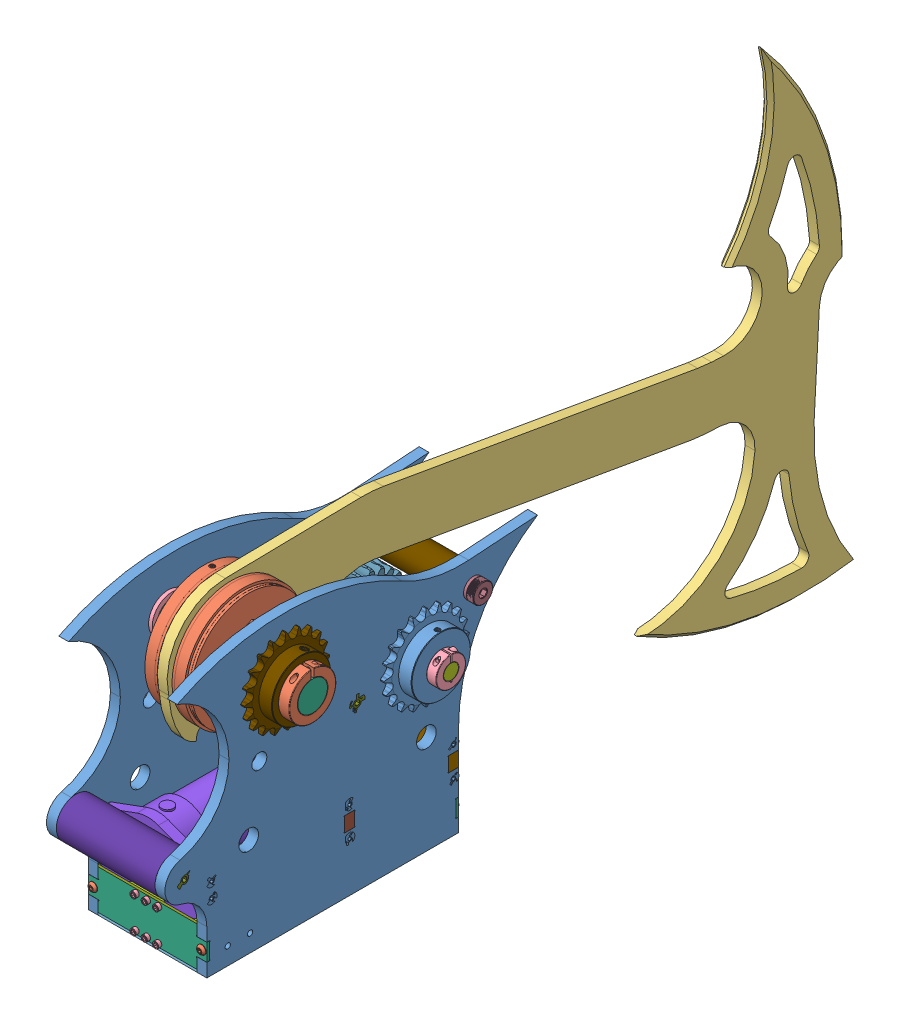
SolidWorks assembly BombshellAxeAsm, configuration Extend. Lengths in mm.
99 component instances, 41 part files, 194 mates.
Components (placement in the parent):
- AxeWeaponRail-1: AxeWeaponRail [Default] at (439.7489 345.0261 495.1514) size (12.7 356.85 479.43)
- AxeWeaponRail-2: AxeWeaponRail [Default] at (300.0489 345.0261 495.1514) size (12.7 356.85 479.43)
- AxeArmAsm-1: AxeArmAsm [Default] at (391.7765 573.6147 629.7988) x (0 -0.054175 -0.998531) z (1 0 0) size (901.7 632 77.46)
  - 6524K135 440ftlb Torque Clutch 1500bore-1: 6524K135 440ftlb Torque Clutch 1500bore [6524K135] at (-33.243 17.2859 43.2099) size (152.4 152.56 77.46)
  - AxeBarV2-1: AxeBarV2 [Default] at (-33.243 17.2859 -17.1151) x (0 0 1) z (-1 0 0) size (12.7 632 901.7)
- 6338K442 1500ID Bushing-1: 6338K442 1500ID Bushing [Default] at (434.9864 592.6761 662.0565) size (38.1 50.8 50.8)
- 6338K442 1500ID Bushing-2: 6338K442 1500ID Bushing [Default] at (317.5114 592.6761 662.0565) x (-1 0 0) z (0 -0.924225 -0.381849) size (38.1 50.8 50.8)
- AxePodBottom-1: AxePodBottom [Default] at (439.7489 300.5761 752.19) x (0 0 -1) z (1 0 0) size (323.85 3.17 127)
- AxePodFrontRearPlate-1: AxePodFrontRearPlate [Default] at (312.7489 303.7511 428.34) size (152.4 50.8 3.18)
- AxePodFrontRearPlate-2: AxePodFrontRearPlate [Default] at (312.7489 303.7511 749.015) size (152.4 50.8 3.18)
- AxePodTop-1: AxePodTop [Default] at (439.7489 354.5511 752.19) x (0 0 -1) z (1 0 0) size (323.85 3.17 127)
- s28400mag-1: s28400mag [Default] at (376.2489 402.1761 739.49) x (0 1 0) z (0 0 -1) size (82.57 82.57 225.04)
- NanoTech 4S 5000mah 130C pack-1: NanoTech 4S 5000mah 130C pack [Default] at (319.0989 340.7511 599.4047) x (0 0 -1) z (0 -1 0) size (178.4 49 37)
- NanoTech 4S 5000mah 130C pack-2: NanoTech 4S 5000mah 130C pack [Default] at (368.0989 340.7511 599.4047) x (0 0 -1) z (0 -1 0) size (178.4 49 37)
- MS2-1: MS2 [Default] at (312.7489 313.1491 682.34) x (0 0 1) z (-1 0 0) size (57.15 41.4 43.43)
- ragebridge2 lpm assembly-1: ragebridge2 lpm assembly [Default] at (323.5439 354.5511 625.19) x (1 0 0) z (0 -1 0) size (105.41 63.5 21.77)
  - heatsink 0002-1: heatsink 0002 [Default] at origin size (93.98 63.5 3.17)
  - ragebridge2 lpm-1: ragebridge2 lpm [Default] at (52.705 25.4 3.175) x (1 0 0) z (0 -1 0) size (105.41 18.6 50.8)
- ragebridge2 lpm assembly-2: ragebridge2 lpm assembly [Default] at (323.5439 303.7511 675.99) x (1 0 0) z (0 1 0) size (105.41 63.5 21.77)
  - heatsink 0002-1: heatsink 0002 [Default] at origin size (93.98 63.5 3.17)
  - ragebridge2 lpm-1: ragebridge2 lpm [Default] at (52.705 25.4 3.175) x (1 0 0) z (0 -1 0) size (105.41 18.6 50.8)
- OrangeRX R410-1: OrangeRX R410 [Default] at (373.9489 346.5511 729.1047) size (15 8 37)
- 57545K213 24T 6P Worm for 0750 Shaft-1: 57545K213 24T 6P Worm for 0750 Shaft [57545K213] at (376.2489 529.1761 482.4514) x (0 0 -1) z (-1 0 0) size (116.49 116.49 50.43)
- Gear48T16P_6325K21 MOD FOR LIFTER-1: Gear48T16P_6325K21 MOD FOR LIFTER [Default] at (376.2489 452.9761 559.023) x (0 0 -1) z (1 0 0) size (25.4 79.5 79.5)
- 57545K227 6P Motor Side Worm for 0875in Shaft-1: 57545K227 6P Motor Side Worm for 0875in Shaft [57545K227] at (376.2489 452.9761 482.4514) size (59.94 60.18 68.33)
- Gear16T16P_6325K13-1: Gear16T16P_6325K13 [Default] at (376.2489 402.1761 559.023) x (0 0 -1) z (1 0 0) size (23.81 28.7 28.7)
- 6280K978 Lifter Large Sprocket-1: 6280K978 Lifter Large Sprocket [6280K978] at (463.155 592.6761 662.0565) x (0 -0.288312 -0.957536) z (1 0 0) size (109.73 109.73 25.4)
- 6280K970 Sprocket 20t Num50 0750Bore-1: 6280K970 Sprocket 20t Num50 0750Bore [6280K97] at (463.155 529.1761 482.4514) x (0 0 -1) z (1 0 0) size (109.73 109.73 25.4)
- 6157K230 1500in Shaft Collar Alu-2: 6157K230 1500in Shaft Collar Alu [6157K23] at (351.6427 592.6761 662.0565) x (0 0 1) z (-1 0 0) size (60.32 60.31 14.37)
- 6157K230 1500in Shaft Collar Alu-3: 6157K230 1500in Shaft Collar Alu [6157K23] at (491.3427 592.6761 662.0565) x (0 0 1) z (-1 0 0) size (60.32 60.31 14.37)
- 6338K431 0750 Bushing-1: 6338K431 0750 Bushing [Default] at (434.9864 529.1761 482.4514) x (-1 0 0) z (0 -0.924225 -0.381849) size (15.88 31.75 31.75)
- 6338K431 0750 Bushing-2: 6338K431 0750 Bushing [Default] at (317.5114 529.1761 482.4514) size (15.88 31.75 31.75)
- 6157K160 0750 Shaft Collar-1: 6157K160 0750 Shaft Collar [6157K16] at (490.5489 529.1761 482.4514) x (0 0 1) z (-1 0 0) size (38.1 38.11 12.77)
- 6157K160 0750 Shaft Collar-2: 6157K160 0750 Shaft Collar [6157K16] at (417.5239 529.1761 482.4514) x (0 0 1) z (-1 0 0) size (38.1 38.11 12.77)
- 6157K160 0750 Shaft Collar-3: 6157K160 0750 Shaft Collar [6157K16] at (357.1989 529.1761 482.4514) x (0 0 1) z (-1 0 0) size (38.1 38.11 12.77)
- 6157K160 0750 Shaft Collar-4: 6157K160 0750 Shaft Collar [6157K16] at (290.5239 529.1761 482.4514) x (0 -0.246824 0.96906) z (-1 0 0) size (38.1 38.11 12.77)
- 6157K230 1500in Shaft Collar Alu-4: 6157K230 1500in Shaft Collar Alu [6157K23] at (289.7302 592.6761 662.0565) x (0 0 -1) z (1 0 0) size (60.32 60.31 14.37)
- 6157K170 0875 Shaft Collar-2: 6157K170 0875 Shaft Collar [6157K17] at (376.2489 452.9761 520.5514) size (41.27 41.28 12.77)
- AxeMainShaft-1: AxeMainShaft [Default] at (390.5364 592.6761 662.0565) x (1 0 0) z (0 0.225652 -0.974208) size (215.9 38.1 38.1)
- AxeChainShaft-1: AxeChainShaft [Default] at (390.5364 529.1761 482.4514) x (1 0 0) z (0 -0.621603 -0.783332) size (212.72 19.05 19.05)
- LongMagRearMount-1: LongMagRearMount [Default] at (376.2489 357.7261 739.49) size (127 84.14 12.7)
- WormShaftMount1-1: WormShaftMount1 [Default] at (376.2489 357.7261 428.34) size (152.4 127 12.7)
- 2868T195 0875 Sleeve Bushing no flange 1125OD-1: 2868T195 0875 Sleeve Bushing no flange 1125OD [2868T195] at (376.2489 452.9761 441.04) size (28.57 28.57 25.4)
- WormShaftMount2-1: WormShaftMount2 [Default] at (376.2489 357.7261 562.198) size (152.4 120.65 12.7)
- 2868T195 0875 Sleeve Bushing no flange 1125OD-2: 2868T195 0875 Sleeve Bushing no flange 1125OD [2868T195] at (376.2489 452.9761 562.198) size (28.57 28.57 25.4)
- LowerWormShaft-1: LowerWormShaft [Default] at (376.2489 452.9761 495.015) x (0 0 -1) z (1 0 0) size (158.75 22.23 22.23)
- 6157K170 0875 Shaft Collar-4: 6157K170 0875 Shaft Collar [6157K17] at (376.2489 452.9761 421.99) x (0.927801 -0.373074 0) z (0 0 1) size (41.27 41.28 12.77)
- 91259A860 0750 Shoulder Bolt for Axe Stop-1: 91259A860 0750 Shoulder Bolt for Axe Stop [91259A860] at (452.4489 564.1011 409.29) x (0 -0.381849 0.924225) z (0 0.924225 0.381849) size (25.4 188.12 25.4)
- 97135A270 0625-11 Locknut-1: 97135A270 0625-11 Locknut [97135A270] at (300.0489 564.1011 409.29) x (0 1 0) z (0 0 1) size (23.81 19.79 27.5)
- module standoffs-1: module standoffs [Default] at (312.7489 424.4011 780.765) size (127 22.23 22.23)
- module standoffs-2: module standoffs [Default] at (312.7489 510.1261 558.515) size (127 22.23 22.23)
- 91253A624-1: 91253A624 [91253A624] at (452.4489 510.1261 558.515) x (0 0 -1) z (1 0 0) size (19.84 19.84 26.24)
- 91253A624-2: 91253A624 [91253A624] at (452.4489 424.4011 780.765) x (0 0 -1) z (1 0 0) size (19.84 19.84 26.24)
- 91253A624-3: 91253A624 [91253A624] at (300.0489 510.1261 558.515) x (0 0 1) z (-1 0 0) size (19.84 19.84 26.24)
- 91253A624-4: 91253A624 [91253A624] at (300.0489 424.4011 780.765) x (0 0 1) z (-1 0 0) size (19.84 19.84 26.24)
- 87235k58 polyurethane tube trimmed to 5in-1: 87235k58 polyurethane tube trimmed to 5in [Default] at (376.2489 424.4011 780.765) size (127 50.8 50.8)
- 9697k158 polyurethane tube trimmed to 5in-1: 9697k158 polyurethane tube trimmed to 5in [Default] at (376.2489 564.1011 409.29) size (127 38.1 38.1)
- 91253A542 0250-20 x 1 FHCS-1: 91253A542 0250-20 x 1 FHCS [91253A542] at (300.0489 405.2646 745.84) x (0 0 1) z (-1 0 0) size (13.49 13.49 26.08)
- 91253A542 0250-20 x 1 FHCS-2: 91253A542 0250-20 x 1 FHCS [91253A542] at (300.0489 386.2146 745.84) x (0 0 1) z (-1 0 0) size (13.49 13.49 26.08)
- 91253A542 0250-20 x 1 FHCS-3: 91253A542 0250-20 x 1 FHCS [91253A542] at (300.0489 402.1761 568.548) x (0 0 1) z (-1 0 0) size (13.49 13.49 26.08)
- 91253A542 0250-20 x 1 FHCS-4: 91253A542 0250-20 x 1 FHCS [91253A542] at (300.0489 364.0761 568.548) x (0 0 1) z (-1 0 0) size (13.49 13.49 26.08)
- 91253A542 0250-20 x 1 FHCS-5: 91253A542 0250-20 x 1 FHCS [91253A542] at (300.0489 402.1761 434.69) x (0 0 1) z (-1 0 0) size (13.49 13.49 26.08)
- 91253A542 0250-20 x 1 FHCS-6: 91253A542 0250-20 x 1 FHCS [91253A542] at (300.0489 364.0761 434.69) x (0 0 1) z (-1 0 0) size (13.49 13.49 26.08)
- 91255A539 0250-20 x 0625 BHCS-1: 91255A539 0250-20 x 0625 BHCS [91255A539] at (306.3989 329.1511 755.5428) size (11.1 11.1 19.9)
- 91255A539 0250-20 x 0625 BHCS-2: 91255A539 0250-20 x 0625 BHCS [91255A539] at (306.3989 329.1511 424.9872) x (-0.923728 -0.383049 0) z (0 0 -1) size (11.1 11.1 19.9)
- 91253A542 0250-20 x 1 FHCS-7: 91253A542 0250-20 x 1 FHCS [91253A542] at (452.4489 405.2646 745.84) x (0 0 1) z (1 0 0) size (13.49 13.49 26.08)
- 91253A542 0250-20 x 1 FHCS-8: 91253A542 0250-20 x 1 FHCS [91253A542] at (452.4489 386.2146 745.84) x (0 0 1) z (1 0 0) size (13.49 13.49 26.08)
- 91253A542 0250-20 x 1 FHCS-9: 91253A542 0250-20 x 1 FHCS [91253A542] at (452.4489 402.1761 568.548) x (0 0 1) z (1 0 0) size (13.49 13.49 26.08)
- 91253A542 0250-20 x 1 FHCS-10: 91253A542 0250-20 x 1 FHCS [91253A542] at (452.4489 364.0761 568.548) x (0 0 1) z (1 0 0) size (13.49 13.49 26.08)
- 91253A542 0250-20 x 1 FHCS-11: 91253A542 0250-20 x 1 FHCS [91253A542] at (452.4489 402.1761 434.69) x (0 0 1) z (1 0 0) size (13.49 13.49 26.08)
- 91253A542 0250-20 x 1 FHCS-12: 91253A542 0250-20 x 1 FHCS [91253A542] at (452.4489 364.0761 434.69) x (0 0 1) z (1 0 0) size (13.49 13.49 26.08)
- 91255A539 0250-20 x 0625 BHCS-3: 91255A539 0250-20 x 0625 BHCS [91255A539] at (446.0989 329.1511 755.5428) x (-1 0 0) z (0 0 1) size (11.1 11.1 19.9)
- 91255A539 0250-20 x 0625 BHCS-4: 91255A539 0250-20 x 0625 BHCS [91255A539] at (446.0989 329.1511 424.9872) x (0.923728 -0.383049 0) z (0 0 -1) size (11.1 11.1 19.9)
- 3x2 Medium Nutstrip-1: 3x2 Medium Nutstrip [Default] at (357.1989 308.5136 436.2775) x (1 0 0) z (0 1 0) size (38.1 9.53 9.53)
- 3x2 Medium Nutstrip-2: 3x2 Medium Nutstrip [Default] at (357.1989 349.7886 436.2775) x (1 0 0) z (0 1 0) size (38.1 9.53 9.53)
- 3x2 Medium Nutstrip-3: 3x2 Medium Nutstrip [Default] at (357.1989 349.7886 744.2525) x (1 0 0) z (0 1 0) size (38.1 9.53 9.53)
- 3x2 Medium Nutstrip-4: 3x2 Medium Nutstrip [Default] at (357.1989 308.5136 744.2525) x (1 0 0) z (0 1 0) size (38.1 9.53 9.53)
- 91251A242 10-24 SHCS 0500L-1: 91251A242 10-24 SHCS 0500L [91251A242] at (390.7489 308.5136 739.49) x (-0.923728 -0.383049 0) z (0 0 -1) size (7.92 7.92 18.68)
- 91253A242 10-24x0500 FHCS-1: 91253A242 10-24x0500 FHCS [91253A242] at (368.9989 300.5761 744.2525) x (1 0 0) z (0 -1 0) size (10.44 10.44 25.75)
- 91251A242 10-24 SHCS 0500L-2: 91251A242 10-24 SHCS 0500L [91251A242] at (376.2489 308.5136 739.49) x (-0.923728 -0.383049 0) z (0 0 -1) size (7.92 7.92 18.68)
- 91251A242 10-24 SHCS 0500L-3: 91251A242 10-24 SHCS 0500L [91251A242] at (361.7489 308.5136 739.49) x (-0.923728 -0.383049 0) z (0 0 -1) size (7.92 7.92 18.68)
- 91251A242 10-24 SHCS 0500L-4: 91251A242 10-24 SHCS 0500L [91251A242] at (390.7489 349.7886 739.49) x (-0.923728 -0.383049 0) z (0 0 -1) size (7.92 7.92 18.68)
- 91251A242 10-24 SHCS 0500L-5: 91251A242 10-24 SHCS 0500L [91251A242] at (376.2489 349.7886 739.49) x (-0.923728 -0.383049 0) z (0 0 -1) size (7.92 7.92 18.68)
- 91251A242 10-24 SHCS 0500L-6: 91251A242 10-24 SHCS 0500L [91251A242] at (361.7489 349.7886 739.49) x (-0.923728 -0.383049 0) z (0 0 -1) size (7.92 7.92 18.68)
- 91251A242 10-24 SHCS 0500L-7: 91251A242 10-24 SHCS 0500L [91251A242] at (368.9989 345.0261 744.2525) x (1 0 0) z (0 -1 0) size (7.92 7.92 18.68)
- 91251A242 10-24 SHCS 0500L-8: 91251A242 10-24 SHCS 0500L [91251A242] at (383.4989 345.0261 744.2525) x (1 0 0) z (0 -1 0) size (7.92 7.92 18.68)
- 91251A242 10-24 SHCS 0500L-9: 91251A242 10-24 SHCS 0500L [91251A242] at (390.7489 308.5136 441.04) size (7.92 7.92 18.68)
- 91251A242 10-24 SHCS 0500L-10: 91251A242 10-24 SHCS 0500L [91251A242] at (376.2489 308.5136 441.04) size (7.92 7.92 18.68)
- 91251A242 10-24 SHCS 0500L-11: 91251A242 10-24 SHCS 0500L [91251A242] at (361.7489 308.5136 441.04) size (7.92 7.92 18.68)
- 91251A242 10-24 SHCS 0500L-12: 91251A242 10-24 SHCS 0500L [91251A242] at (390.7489 349.7886 441.04) size (7.92 7.92 18.68)
- 91251A242 10-24 SHCS 0500L-13: 91251A242 10-24 SHCS 0500L [91251A242] at (376.2489 349.7886 441.04) size (7.92 7.92 18.68)
- 91251A242 10-24 SHCS 0500L-14: 91251A242 10-24 SHCS 0500L [91251A242] at (361.7489 349.7886 441.04) size (7.92 7.92 18.68)
- 91251A242 10-24 SHCS 0500L-15: 91251A242 10-24 SHCS 0500L [91251A242] at (368.9989 345.0261 436.2775) x (1 0 0) z (0 -1 0) size (7.92 7.92 18.68)
- 91251A242 10-24 SHCS 0500L-16: 91251A242 10-24 SHCS 0500L [91251A242] at (383.4989 345.0261 436.2775) x (1 0 0) z (0 -1 0) size (7.92 7.92 18.68)
- 91253A242 10-24x0500 FHCS-2: 91253A242 10-24x0500 FHCS [91253A242] at (383.4989 300.5761 744.2525) x (1 0 0) z (0 -1 0) size (10.44 10.44 25.75)
- 91253A242 10-24x0500 FHCS-3: 91253A242 10-24x0500 FHCS [91253A242] at (368.9989 300.5761 436.2775) x (1 0 0) z (0 -1 0) size (10.44 10.44 25.75)
- 91253A242 10-24x0500 FHCS-4: 91253A242 10-24x0500 FHCS [91253A242] at (383.4989 300.5761 436.2775) x (1 0 0) z (0 -1 0) size (10.44 10.44 25.75)
- 91253A542 0250-20 x 1 FHCS-13: 91253A542 0250-20 x 1 FHCS [91253A542] at (300.0489 322.8011 696.564) x (0 0 1) z (-1 0 0) size (13.49 13.49 26.08)
- 91253A542 0250-20 x 1 FHCS-14: 91253A542 0250-20 x 1 FHCS [91253A542] at (300.0489 322.8011 725.266) x (0 0 1) z (-1 0 0) size (13.49 13.49 26.08)
Mates (geometry in assembly coordinates):
- Distance7: distance = 4.7625 mm anti-aligned: plane of AxeWeaponRail-1 through (439.7489 345.0261 495.1514) normal (-1 0 0); plane of AxeArmAsm-1/6524K135 440ftlb Torque Clutch 1500bore-1 through (434.9864 611.6982 661.0245) normal (1 0 0)
- Coincident64: coincident anti-aligned: plane of AxeWeaponRail-1 through (439.7489 345.0261 495.1514) normal (-1 0 0); plane of 6338K442 1500ID Bushing-1 through (439.7489 592.6761 662.0565) normal (1 0 0)
- Coincident65: coincident anti-aligned: plane of AxeWeaponRail-2 through (312.7489 345.0261 495.1514) normal (1 0 0); plane of 6338K442 1500ID Bushing-2 through (312.7489 592.6761 662.0565) normal (-1 0 0)
- Concentric60: concentric aligned: cylinder of AxeWeaponRail-1 through (439.7489 427.5761 469.7514) axis (1 0 0) radius 12.7; cylinder of AxeWeaponRail-2 through (300.0489 427.5761 469.7514) axis (1 0 0) radius 12.7
- Concentric61: concentric aligned: cylinder of AxeWeaponRail-1 through (439.7489 427.5761 698.3514) axis (1 0 0) radius 12.7; cylinder of AxeWeaponRail-2 through (300.0489 427.5761 698.3514) axis (1 0 0) radius 12.7
- Distance8: distance = 152.4 mm anti-aligned: plane of AxeWeaponRail-2 through (300.0489 345.0261 495.1514) normal (-1 0 0); plane of AxeWeaponRail-1 through (452.4489 345.0261 495.1514) normal (1 0 0)
- Coincident66: coincident anti-aligned: plane of AxeWeaponRail-2 through (312.7489 345.0261 495.1514) normal (1 0 0); plane of AxePodBottom-1 through (312.7489 303.7511 752.19) normal (-1 0 0)
- Coincident67: coincident aligned: plane of AxeWeaponRail-1 through (439.7489 418.1311 428.34) normal (0 0 -1); plane of AxePodBottom-1 through (439.7489 303.7511 428.34) normal (0 0 -1)
- Coincident68: coincident aligned: plane of AxeWeaponRail-1 through (452.4489 300.5761 495.1514) normal (0 -1 0); plane of AxePodBottom-1 through (439.7489 300.5761 752.19) normal (0 -1 0)
- Coincident75: coincident anti-aligned: plane of AxeWeaponRail-1 through (439.7489 345.0261 495.1514) normal (-1 0 0); plane of AxePodTop-1 through (439.7489 357.7261 752.19) normal (1 0 0)
- Coincident77: coincident aligned: plane of AxeWeaponRail-1 through (439.7489 418.1311 428.34) normal (0 0 -1); plane of AxePodTop-1 through (439.7489 357.7261 428.34) normal (0 0 -1)
- Parallel1: parallel aligned: plane of AxeWeaponRail-1 through (439.7489 300.5761 752.19) normal (0 0 1); plane of s28400mag-1 through (376.2489 402.1761 739.49) normal (0 0 1)
- Distance9: distance = 12.7 mm aligned: plane of s28400mag-1 through (376.2489 402.1761 739.49) normal (0 0 1); plane of AxeWeaponRail-1 through (439.7489 300.5761 752.19) normal (0 0 1)
- Distance11: distance = 57.15 mm anti-aligned: cylinder of s28400mag-1 through (376.2489 402.1761 755.492) axis (0 0 -1) radius 6.35; plane of AxeWeaponRail-1 through (439.7489 345.0261 495.1514) normal (-1 0 0)
- Coincident78: coincident aligned: plane of NanoTech 4S 5000mah 130C pack-1 through (368.0989 340.7511 599.4047) normal (0 1 0); plane of NanoTech 4S 5000mah 130C pack-2 through (417.0989 340.7511 599.4047) normal (0 1 0)
- Coincident79: coincident aligned: plane of NanoTech 4S 5000mah 130C pack-1 through (368.0989 340.7511 599.4047) normal (0 0 1); plane of NanoTech 4S 5000mah 130C pack-2 through (417.0989 340.7511 599.4047) normal (0 0 1)
- Coincident80: coincident anti-aligned: plane of NanoTech 4S 5000mah 130C pack-1 through (368.0989 340.7511 599.4047) normal (1 0 0); plane of NanoTech 4S 5000mah 130C pack-2 through (368.0989 340.7511 599.4047) normal (-1 0 0)
- Coincident81: coincident anti-aligned: plane of AxePodBottom-1 through (439.7489 303.7511 752.19) normal (0 1 0); plane of NanoTech 4S 5000mah 130C pack-1 through (368.0989 303.7511 599.4047) normal (0 -1 0)
- Parallel3: parallel anti-aligned: plane of AxeWeaponRail-2 through (312.7489 345.0261 495.1514) normal (1 0 0); plane of NanoTech 4S 5000mah 130C pack-1 through (319.0989 340.7511 599.4047) normal (-1 0 0)
- Distance12: distance = 6.35 mm anti-aligned: plane of AxeWeaponRail-2 through (312.7489 345.0261 495.1514) normal (1 0 0); plane of NanoTech 4S 5000mah 130C pack-1 through (319.0989 340.7511 599.4047) normal (-1 0 0)
- Coincident83: coincident anti-aligned: plane of AxeWeaponRail-2 through (312.7489 345.0261 495.1514) normal (1 0 0); plane of MS2-1 through (312.7489 354.5511 682.34) normal (-1 0 0)
- Coincident85: coincident anti-aligned: plane of AxePodTop-1 through (439.7489 354.5511 752.19) normal (0 -1 0); plane of ragebridge2 lpm assembly-1/heatsink 0002-1 through (421.9689 354.5511 618.205) normal (0 1 0)
- Distance15: distance = 10.795 mm anti-aligned: plane of AxeWeaponRail-1 through (439.7489 345.0261 495.1514) normal (-1 0 0); plane of ragebridge2 lpm assembly-1/ragebridge2 lpm-1 through (428.9539 351.3761 625.19) normal (1 0 0)
- Concentric62: concentric aligned: cylinder of ragebridge2 lpm assembly-1/heatsink 0002-1 through (414.3489 354.5511 679.165) axis (0 -1 0) radius 1.4605; cylinder of ragebridge2 lpm assembly-2/heatsink 0002-1 through (414.3489 306.9261 679.165) axis (0 -1 0) radius 1.4605
- Concentric63: concentric aligned: cylinder of ragebridge2 lpm assembly-1/heatsink 0002-1 through (338.1489 351.3761 622.015) axis (0 1 0) radius 1.4605; cylinder of ragebridge2 lpm assembly-2/heatsink 0002-1 through (338.1489 303.7511 622.015) axis (0 1 0) radius 1.4605
- Distance17: distance = 50.8 mm aligned: plane of ragebridge2 lpm assembly-2/heatsink 0002-1 through (421.9689 303.7511 682.975) normal (0 -1 0); plane of AxePodTop-1 through (439.7489 354.5511 752.19) normal (0 -1 0)
- Coincident89: coincident anti-aligned: plane of AxePodTop-1 through (439.7489 354.5511 752.19) normal (0 -1 0); plane of OrangeRX R410-1 through (373.9489 354.5511 729.1047) normal (0 1 0)
- Distance19: distance = 50.8 mm anti-aligned: plane of OrangeRX R410-1 through (388.9489 354.5511 729.1047) normal (1 0 0); plane of AxeWeaponRail-1 through (439.7489 345.0261 495.1514) normal (-1 0 0)
- Coincident92: coincident anti-aligned: plane of AxePodTop-1 through (439.7489 354.5511 752.19) normal (0 -1 0); plane of MS2-1 through (341.4509 354.5511 682.34) normal (0 1 0)
- Coincident93: coincident aligned: plane of Gear48T16P_6325K21 MOD FOR LIFTER-1 through (376.2489 452.9761 559.023) normal (0 0 1); plane of Gear16T16P_6325K13-1 through (376.2489 402.1761 559.023) normal (0 0 1)
- Distance20: distance = 33.3375 mm: cylinder of Gear48T16P_6325K21 MOD FOR LIFTER-1 through (376.2489 452.9761 533.623) axis (0 0 1) radius 11.1125; cylinder of Gear16T16P_6325K13-1 through (376.2489 402.1761 535.2105) axis (0 0 1) radius 6.35
- Parallel4: parallel anti-aligned: plane of s28400mag-1 through (376.2489 402.1761 566.008) normal (0 0 -1); plane of Gear16T16P_6325K13-1 through (376.2489 402.1761 559.023) normal (0 0 1)
- Concentric65: concentric aligned: cylinder of s28400mag-1 through (376.2489 402.1761 530.448) axis (0 0 1) radius 6.35; cylinder of Gear16T16P_6325K13-1 through (376.2489 402.1761 535.2105) axis (0 0 1) radius 6.35
- Distance21: distance = 9.525 mm anti-aligned: plane of Gear16T16P_6325K13-1 through (376.2489 402.1761 559.023) normal (0 0 1); plane of s28400mag-1 through (376.2489 402.1761 568.548) normal (0 0 -1)
- Concentric66: concentric aligned: cylinder of Gear48T16P_6325K21 MOD FOR LIFTER-1 through (376.2489 452.9761 533.623) axis (0 0 1) radius 11.1125; cylinder of 57545K227 6P Motor Side Worm for 0875in Shaft-1 through (376.2489 452.9761 482.4514) axis (0 0 1) radius 11.1125
- Parallel5: parallel aligned: plane of AxeWeaponRail-1 through (439.7489 345.0261 495.1514) normal (-1 0 0); plane of 57545K227 6P Motor Side Worm for 0875in Shaft-1 through (378.6302 463.1742 448.1299) normal (-1 0 0)
- Coincident95: coincident aligned: plane of Gear48T16P_6325K21 MOD FOR LIFTER-1 through (378.6302 452.9761 533.623) normal (-1 0 0); plane of 57545K227 6P Motor Side Worm for 0875in Shaft-1 through (378.6302 463.1742 448.1299) normal (-1 0 0)
- Coincident96: coincident anti-aligned: plane of 57545K213 24T 6P Worm for 0750 Shaft-1 through (376.2489 529.1761 482.4514) normal (-1 0 0); plane of 57545K227 6P Motor Side Worm for 0875in Shaft-1 through (376.2489 452.9761 482.4514) normal (1 0 0)
- Coincident97: coincident anti-aligned: plane of 57545K213 24T 6P Worm for 0750 Shaft-1; plane of 57545K227 6P Motor Side Worm for 0875in Shaft-1 through (376.2489 452.9761 482.4514) normal (0 0 1)
- Distance22: distance = 76.2 mm anti-aligned: plane of 57545K227 6P Motor Side Worm for 0875in Shaft-1 through (376.2489 452.9761 482.4514) normal (0 1 0); plane of 57545K213 24T 6P Worm for 0750 Shaft-1
- Distance23: distance = 52.3875 mm anti-aligned: cylinder of 57545K227 6P Motor Side Worm for 0875in Shaft-1 through (376.2489 452.9761 482.4514) axis (0 0 1) radius 11.1125; plane of AxeWeaponRail-2 through (312.7489 345.0261 495.1514) normal (1 0 0)
- Concentric67: concentric aligned: cylinder of 6338K442 1500ID Bushing-1 through (473.0864 592.6761 662.0565) axis (-1 0 0) radius 19.05; cylinder of 6280K978 Lifter Large Sprocket-1 through (484.1989 592.6761 662.0565) axis (-1 0 0) radius 19.05
- Distance24: distance = 6.35 mm anti-aligned: plane of AxeWeaponRail-1 through (452.4489 345.0261 495.1514) normal (1 0 0); plane of 6280K978 Lifter Large Sprocket-1 through (458.7989 547.729 675.59) normal (-1 0 0)
- Coincident100: coincident aligned: plane of 6280K978 Lifter Large Sprocket-1 through (458.7989 547.729 675.59) normal (-1 0 0); plane of 6280K970 Sprocket 20t Num50 0750Bore-1 through (458.7989 482.2357 482.4514) normal (-1 0 0)
- Concentric68: concentric anti-aligned: cylinder of AxeWeaponRail-1 through (439.7489 529.1761 482.4514) axis (1 0 0) radius 12.7; cylinder of 6280K970 Sprocket 20t Num50 0750Bore-1 through (484.1989 529.1761 482.4514) axis (-1 0 0) radius 9.525
- Coincident101: coincident aligned: plane of 57545K213 24T 6P Worm for 0750 Shaft-1; plane of 6280K970 Sprocket 20t Num50 0750Bore-1 through (463.155 529.1761 482.4514) normal (0 0 -1)
- Concentric70: concentric anti-aligned: cylinder of 6280K978 Lifter Large Sprocket-1 through (484.1989 592.6761 662.0565) axis (-1 0 0) radius 19.05; cylinder of 6157K230 1500in Shaft Collar Alu-3 through (484.1989 592.6761 662.0565) axis (1 0 0) radius 19.05
- Concentric71: concentric anti-aligned: cylinder of 6280K978 Lifter Large Sprocket-1 through (484.1989 592.6761 662.0565) axis (-1 0 0) radius 19.05; cylinder of 6157K230 1500in Shaft Collar Alu-2 through (344.4989 592.6761 662.0565) axis (1 0 0) radius 19.05
- Coincident102: coincident aligned: circle of AxeArmAsm-1/6524K135 440ftlb Torque Clutch 1500bore-1; plane of 6157K230 1500in Shaft Collar Alu-2 through (358.7864 592.6761 662.0565) normal (1 0 0)
- Coincident103: coincident anti-aligned: plane of 6280K978 Lifter Large Sprocket-1 through (484.1989 592.6761 662.0565) normal (1 0 0); plane of 6157K230 1500in Shaft Collar Alu-3 through (484.1989 592.6761 662.0565) normal (-1 0 0)
- Concentric72: concentric aligned: cylinder of AxeWeaponRail-2 through (300.0489 529.1761 482.4514) axis (1 0 0) radius 12.7; cylinder of 6338K431 0750 Bushing-2 through (301.6364 529.1761 482.4514) axis (1 0 0) radius 12.7
- Concentric73: concentric anti-aligned: cylinder of AxeWeaponRail-2 through (300.0489 529.1761 482.4514) axis (1 0 0) radius 12.7; cylinder of 6338K431 0750 Bushing-1 through (450.8614 529.1761 482.4514) axis (-1 0 0) radius 12.7
- Coincident104: coincident anti-aligned: plane of AxeWeaponRail-1 through (439.7489 345.0261 495.1514) normal (-1 0 0); plane of 6338K431 0750 Bushing-1 through (439.7489 529.1761 482.4514) normal (1 0 0)
- Coincident105: coincident anti-aligned: plane of AxeWeaponRail-2 through (312.7489 345.0261 495.1514) normal (1 0 0); plane of 6338K431 0750 Bushing-2 through (312.7489 529.1761 482.4514) normal (-1 0 0)
- Concentric74: concentric aligned: cylinder of 6338K431 0750 Bushing-2 through (301.6364 529.1761 482.4514) axis (1 0 0) radius 9.5504; cylinder of 6157K160 0750 Shaft Collar-1 through (484.1989 529.1761 482.4514) axis (1 0 0) radius 9.525
- Concentric75: concentric aligned: cylinder of 6157K160 0750 Shaft Collar-1 through (484.1989 529.1761 482.4514) axis (1 0 0) radius 9.525; cylinder of 6157K160 0750 Shaft Collar-2 through (411.1739 529.1761 482.4514) axis (1 0 0) radius 9.525
- Concentric76: concentric aligned: cylinder of 6157K160 0750 Shaft Collar-2 through (411.1739 529.1761 482.4514) axis (1 0 0) radius 9.525; cylinder of 6157K160 0750 Shaft Collar-3 through (350.8489 529.1761 482.4514) axis (1 0 0) radius 9.525
- Concentric77: concentric aligned: cylinder of 6157K160 0750 Shaft Collar-3 through (350.8489 529.1761 482.4514) axis (1 0 0) radius 9.525; cylinder of 6157K160 0750 Shaft Collar-4 through (284.1739 529.1761 482.4514) axis (1 0 0) radius 9.525
- Coincident106: coincident anti-aligned: plane of 6280K970 Sprocket 20t Num50 0750Bore-1 through (484.1989 529.1761 482.4514) normal (1 0 0); plane of 6157K160 0750 Shaft Collar-1 through (484.1989 529.1761 482.4514) normal (-1 0 0)
- Coincident107: coincident anti-aligned: plane of 57545K213 24T 6P Worm for 0750 Shaft-1 through (411.1739 505.3636 482.4514) normal (1 0 0); plane of 6157K160 0750 Shaft Collar-2 through (411.1739 529.1761 482.4514) normal (-1 0 0)
- Coincident108: coincident anti-aligned: plane of 57545K213 24T 6P Worm for 0750 Shaft-1 through (363.5489 474.5872 482.4514) normal (-1 0 0); plane of 6157K160 0750 Shaft Collar-3 through (363.5489 529.1761 482.4514) normal (1 0 0)
- Distance26: distance = 3.175 mm anti-aligned: plane of 6157K160 0750 Shaft Collar-4 through (296.8739 529.1761 482.4514) normal (1 0 0); plane of AxeWeaponRail-2 through (300.0489 345.0261 495.1514) normal (-1 0 0)
- Distance27: distance = 3.175 mm anti-aligned: plane of 6157K230 1500in Shaft Collar Alu-4 through (296.8739 592.6761 662.0565) normal (1 0 0); plane of AxeWeaponRail-2 through (300.0489 345.0261 495.1514) normal (-1 0 0)
- Coincident111: coincident anti-aligned: plane of 57545K227 6P Motor Side Worm for 0875in Shaft-1 through (376.2489 479.0789 514.2014) normal (0 0 1); plane of 6157K170 0875 Shaft Collar-2 through (376.2489 452.9761 514.2014) normal (0 0 -1)
- Coincident113: coincident anti-aligned: circle of 6157K230 1500in Shaft Collar Alu-3; cylinder of AxeMainShaft-1 through (498.4864 592.6761 662.0565) axis (-1 0 0) radius 19.05
- Coincident114: coincident aligned: plane of 6157K230 1500in Shaft Collar Alu-3 through (498.4864 592.6761 662.0565) normal (1 0 0); plane of AxeMainShaft-1 through (498.4864 592.6761 662.0565) normal (1 0 0)
- Coincident115: coincident aligned: plane of 6157K160 0750 Shaft Collar-1 through (496.8989 529.1761 482.4514) normal (1 0 0); plane of AxeChainShaft-1 through (496.8989 529.1761 482.4514) normal (1 0 0)
- Concentric82: concentric anti-aligned: cylinder of 6157K160 0750 Shaft Collar-1 through (484.1989 529.1761 482.4514) axis (1 0 0) radius 9.525; cylinder of AxeChainShaft-1 through (496.8989 529.1761 482.4514) axis (-1 0 0) radius 9.525
- Coincident116: coincident anti-aligned: plane of AxePodTop-1 through (439.7489 357.7261 752.19) normal (0 1 0); plane of LongMagRearMount-1 through (312.7489 357.7261 752.19) normal (0 -1 0)
- Coincident117: coincident anti-aligned: plane of s28400mag-1 through (376.2489 402.1761 739.49) normal (0 0 1); plane of LongMagRearMount-1 through (376.2489 357.7261 739.49) normal (0 0 -1)
- Coincident118: coincident anti-aligned: plane of AxeWeaponRail-2 through (312.7489 345.0261 495.1514) normal (1 0 0); plane of LongMagRearMount-1 through (312.7489 357.7261 752.19) normal (-1 0 0)
- Coincident119: coincident aligned: plane of AxeWeaponRail-2 through (300.0489 418.1311 428.34) normal (0 0 -1); plane of WormShaftMount1-1 through (376.2489 357.7261 428.34) normal (0 0 -1)
- Coincident120: coincident anti-aligned: plane of AxePodTop-1 through (439.7489 357.7261 752.19) normal (0 1 0); plane of WormShaftMount1-1 through (312.7489 357.7261 441.04) normal (0 -1 0)
- Coincident121: coincident anti-aligned: plane of AxeWeaponRail-2 through (312.7489 345.0261 495.1514) normal (1 0 0); plane of WormShaftMount1-1 through (312.7489 357.7261 441.04) normal (-1 0 0)
- Concentric83: concentric anti-aligned: cylinder of WormShaftMount1-1 through (376.2489 452.9761 428.34) axis (0 0 1) radius 14.2875; cylinder of 2868T195 0875 Sleeve Bushing no flange 1125OD-1 through (376.2489 452.9761 453.74) axis (0 0 -1) radius 11.1252
- Coincident122: coincident aligned: plane of WormShaftMount1-1 through (376.2489 357.7261 428.34) normal (0 0 -1); plane of 2868T195 0875 Sleeve Bushing no flange 1125OD-1 through (376.2489 452.9761 428.34) normal (0 0 -1)
- Coincident123: coincident anti-aligned: plane of AxeWeaponRail-2 through (312.7489 345.0261 495.1514) normal (1 0 0); plane of WormShaftMount2-1 through (312.7489 357.7261 574.898) normal (-1 0 0)
- Coincident124: coincident anti-aligned: plane of AxePodTop-1 through (439.7489 357.7261 752.19) normal (0 1 0); plane of WormShaftMount2-1 through (312.7489 357.7261 574.898) normal (0 -1 0)
- Distance28: distance = 6.35 mm aligned: plane of WormShaftMount2-1 through (376.2489 357.7261 562.198) normal (0 0 -1); plane of s28400mag-1 through (376.2489 402.1761 568.548) normal (0 0 -1)
- Coincident125: coincident aligned: plane of WormShaftMount2-1 through (376.2489 357.7261 574.898) normal (0 0 1); plane of 2868T195 0875 Sleeve Bushing no flange 1125OD-2 through (376.2489 452.9761 574.898) normal (0 0 1)
- Concentric84: concentric aligned: cylinder of WormShaftMount2-1 through (376.2489 452.9761 574.898) axis (0 0 -1) radius 14.2875; cylinder of 2868T195 0875 Sleeve Bushing no flange 1125OD-2 through (376.2489 452.9761 574.898) axis (0 0 -1) radius 14.2875
- Concentric85: concentric anti-aligned: cylinder of 2868T195 0875 Sleeve Bushing no flange 1125OD-1 through (376.2489 452.9761 453.74) axis (0 0 -1) radius 11.1252; cylinder of LowerWormShaft-1 through (376.2489 452.9761 415.64) axis (0 0 1) radius 11.1125
- Coincident127: coincident aligned: circle of LowerWormShaft-1; cylinder of 6157K170 0875 Shaft Collar-4 through (376.2489 452.9761 428.34) axis (0 0 -1) radius 11.1125
- Coincident128: coincident anti-aligned: plane of WormShaftMount1-1 through (376.2489 357.7261 428.34) normal (0 0 -1); plane of 6157K170 0875 Shaft Collar-4 through (376.2489 452.9761 428.34) normal (0 0 1)
- Coincident129: coincident aligned: plane of LowerWormShaft-1 through (376.2489 452.9761 415.64) normal (0 0 -1); plane of 6157K170 0875 Shaft Collar-4 through (376.2489 452.9761 415.64) normal (0 0 -1)
- Coincident130: coincident anti-aligned: plane of AxeWeaponRail-1 through (452.4489 345.0261 495.1514) normal (1 0 0); plane of 91259A860 0750 Shoulder Bolt for Axe Stop-1 through (452.4489 564.1011 409.29) normal (-1 0 0)
- Coincident131: coincident anti-aligned: plane of AxeWeaponRail-2 through (300.0489 345.0261 495.1514) normal (-1 0 0); plane of 97135A270 0625-11 Locknut-1 through (300.0489 564.1011 395.5418) normal (1 0 0)
- Concentric87: concentric anti-aligned: circle of 91259A860 0750 Shoulder Bolt for Axe Stop-1; circle of 97135A270 0625-11 Locknut-1
- Distance29: distance = 50.8 mm anti-aligned: plane of AxePodTop-1 through (439.7489 354.5511 752.19) normal (0 -1 0); plane of AxePodBottom-1 through (439.7489 303.7511 752.19) normal (0 1 0)
- Coincident132: coincident anti-aligned: plane of AxeWeaponRail-2 through (312.7489 345.0261 495.1514) normal (1 0 0); plane of AxePodFrontRearPlate-2 through (312.7489 303.7511 752.19) normal (-1 0 0)
- Coincident133: coincident aligned: plane of AxeWeaponRail-2 through (300.0489 300.5761 752.19) normal (0 0 1); plane of AxePodFrontRearPlate-2 through (312.7489 303.7511 752.19) normal (0 0 1)
- Coincident134: coincident anti-aligned: plane of AxePodBottom-1 through (439.7489 303.7511 752.19) normal (0 1 0); plane of AxePodFrontRearPlate-2 through (312.7489 303.7511 752.19) normal (0 -1 0)
- Coincident135: coincident aligned: plane of AxePodFrontRearPlate-1 through (452.4489 340.2636 402.7423) normal (1 0 0); plane of AxePodFrontRearPlate-2 through (452.4489 340.2636 723.4173) normal (1 0 0)
- Coincident137: coincident aligned: plane of AxePodFrontRearPlate-1 through (439.7489 340.2636 402.7423) normal (0 1 0); plane of AxePodFrontRearPlate-2 through (439.7489 340.2636 723.4173) normal (0 1 0)
- Coincident138: coincident aligned: plane of AxeWeaponRail-2 through (300.0489 418.1311 428.34) normal (0 0 -1); plane of AxePodFrontRearPlate-1 through (312.7489 303.7511 428.34) normal (0 0 -1)
- Coincident139: coincident aligned: plane of module standoffs-1 through (312.7489 424.4011 780.765) normal (-1 0 0); plane of module standoffs-2 through (312.7489 510.1261 558.515) normal (-1 0 0)
- Coincident141: coincident anti-aligned: plane of AxeWeaponRail-2 through (312.7489 345.0261 495.1514) normal (1 0 0); plane of module standoffs-1 through (312.7489 424.4011 780.765) normal (-1 0 0)
- Concentric88: concentric aligned: cylinder of AxeWeaponRail-2 through (300.0489 424.4011 780.765) axis (-1 0 0) radius 5.0419; cylinder of module standoffs-1 through (439.7489 424.4011 780.765) axis (-1 0 0) radius 3.9688
- Concentric89: concentric aligned: cylinder of AxeWeaponRail-2 through (300.0489 510.1261 558.515) axis (-1 0 0) radius 5.0419; cylinder of module standoffs-2 through (439.7489 510.1261 558.515) axis (-1 0 0) radius 3.9688
- Coincident142: coincident aligned: plane of 91253A624-1 through (452.4489 505.3636 558.515) normal (1 0 0); plane of 91253A624-2 through (452.4489 419.6386 780.765) normal (1 0 0)
- Coincident143: coincident aligned: plane of 91253A624-3 through (300.0489 505.3636 558.515) normal (-1 0 0); plane of 91253A624-4 through (300.0489 419.6386 780.765) normal (-1 0 0)
- Coincident144: coincident aligned: plane of AxeWeaponRail-1 through (452.4489 345.0261 495.1514) normal (1 0 0); plane of 91253A624-2 through (452.4489 419.6386 780.765) normal (1 0 0)
- Coincident145: coincident aligned: plane of AxeWeaponRail-2 through (300.0489 345.0261 495.1514) normal (-1 0 0); plane of 91253A624-3 through (300.0489 505.3636 558.515) normal (-1 0 0)
- Concentric90: concentric aligned: circle of AxeWeaponRail-2; circle of 91253A624-3
- Concentric91: concentric aligned: circle of AxeWeaponRail-2; circle of 91253A624-4
- Concentric92: concentric anti-aligned: circle of AxeWeaponRail-1; circle of 91253A624-1
- Concentric93: concentric anti-aligned: circle of AxeWeaponRail-1; circle of 91253A624-2
- Coincident146: coincident anti-aligned: plane of AxeWeaponRail-1 through (439.7489 345.0261 495.1514) normal (-1 0 0); plane of 87235k58 polyurethane tube trimmed to 5in-1 through (439.7489 424.4011 780.765) normal (1 0 0)
- Concentric94: concentric aligned: cylinder of module standoffs-1 through (439.7489 424.4011 780.765) axis (-1 0 0) radius 11.1125; cylinder of 87235k58 polyurethane tube trimmed to 5in-1 through (439.7489 424.4011 780.765) axis (-1 0 0) radius 12.7
- Coincident147: coincident anti-aligned: plane of AxeWeaponRail-1 through (439.7489 345.0261 495.1514) normal (-1 0 0); plane of 9697k158 polyurethane tube trimmed to 5in-1 through (439.7489 564.1011 409.29) normal (1 0 0)
- Concentric95: concentric aligned: cylinder of 91259A860 0750 Shoulder Bolt for Axe Stop-1 through (452.4489 564.1011 409.29) axis (-1 0 0) radius 9.525; cylinder of 9697k158 polyurethane tube trimmed to 5in-1 through (439.7489 564.1011 409.29) axis (-1 0 0) radius 9.525
- Coincident148: coincident aligned: plane of 91253A542 0250-20 x 1 FHCS-1 through (300.0489 402.0896 745.84) normal (-1 0 0); plane of 91253A542 0250-20 x 1 FHCS-2 through (300.0489 383.0396 745.84) normal (-1 0 0)
- Coincident149: coincident aligned: plane of 91253A542 0250-20 x 1 FHCS-2 through (300.0489 383.0396 745.84) normal (-1 0 0); plane of 91253A542 0250-20 x 1 FHCS-3 through (300.0489 399.0011 568.548) normal (-1 0 0)
- Coincident150: coincident aligned: plane of 91253A542 0250-20 x 1 FHCS-3 through (300.0489 399.0011 568.548) normal (-1 0 0); plane of 91253A542 0250-20 x 1 FHCS-4 through (300.0489 360.9011 568.548) normal (-1 0 0)
- Coincident151: coincident aligned: plane of 91253A542 0250-20 x 1 FHCS-4 through (300.0489 360.9011 568.548) normal (-1 0 0); plane of 91253A542 0250-20 x 1 FHCS-5 through (300.0489 399.0011 434.69) normal (-1 0 0)
- Coincident152: coincident aligned: plane of 91253A542 0250-20 x 1 FHCS-5 through (300.0489 399.0011 434.69) normal (-1 0 0); plane of 91253A542 0250-20 x 1 FHCS-6 through (300.0489 360.9011 434.69) normal (-1 0 0)
- Coincident153: coincident aligned: plane of AxeWeaponRail-2 through (300.0489 345.0261 495.1514) normal (-1 0 0); plane of 91253A542 0250-20 x 1 FHCS-6 through (300.0489 360.9011 434.69) normal (-1 0 0)
- Concentric96: concentric anti-aligned: circle of AxeWeaponRail-2; circle of 91253A542 0250-20 x 1 FHCS-1
- Concentric97: concentric anti-aligned: circle of AxeWeaponRail-2; circle of 91253A542 0250-20 x 1 FHCS-2
- Concentric98: concentric anti-aligned: circle of AxeWeaponRail-2; circle of 91253A542 0250-20 x 1 FHCS-3
- Concentric99: concentric anti-aligned: circle of AxeWeaponRail-2; circle of 91253A542 0250-20 x 1 FHCS-4
- Concentric100: concentric anti-aligned: circle of AxeWeaponRail-2; circle of 91253A542 0250-20 x 1 FHCS-5
- Concentric101: concentric anti-aligned: circle of AxeWeaponRail-2; circle of 91253A542 0250-20 x 1 FHCS-6
- Concentric102: concentric aligned: cylinder of AxePodFrontRearPlate-2 through (306.3989 329.1511 752.19) axis (0 0 1) radius 3.3782; circle of 91255A539 0250-20 x 0625 BHCS-1
- Coincident154: coincident anti-aligned: plane of AxePodFrontRearPlate-2 through (312.7489 303.7511 752.19) normal (0 0 1); plane of 91255A539 0250-20 x 0625 BHCS-1 through (306.3989 323.6012 752.19) normal (0 0 -1)
- Coincident155: coincident anti-aligned: plane of AxePodFrontRearPlate-1 through (312.7489 303.7511 428.34) normal (0 0 -1); plane of 91255A539 0250-20 x 0625 BHCS-2 through (308.5248 324.0245 428.34) normal (0 0 1)
- Concentric103: concentric aligned: circle of AxePodFrontRearPlate-1; circle of 91255A539 0250-20 x 0625 BHCS-2
- Concentric104: concentric anti-aligned: cylinder of 6157K170 0875 Shaft Collar-2 through (376.2489 452.9761 526.9014) axis (0 0 -1) radius 11.1125; cylinder of LowerWormShaft-1 through (376.2489 452.9761 415.64) axis (0 0 1) radius 11.1125
- Concentric106: concentric aligned: cylinder of 57545K213 24T 6P Worm for 0750 Shaft-1 through (376.2489 529.1761 482.4514) axis (-1 0 0) radius 23.8125; cylinder of AxeChainShaft-1 through (496.8989 529.1761 482.4514) axis (-1 0 0) radius 9.525
- Parallel7: parallel aligned: cylinder of Gear48T16P_6325K21 MOD FOR LIFTER-1 through (376.2489 452.9761 533.623) axis (0 0 1) radius 11.1125; cylinder of LowerWormShaft-1 through (376.2489 452.9761 415.64) axis (0 0 1) radius 11.1125
- Parallel9: parallel aligned: plane of AxePodTop-1 through (439.7489 357.7261 752.19) normal (0 1 0); plane of s28400mag-1 through (376.2489 442.5621 726.79) normal (0 1 0)
- Concentric107: concentric aligned: cylinder of AxeWeaponRail-1 through (452.4489 564.1011 409.29) axis (-1 0 0) radius 9.525; cylinder of 91259A860 0750 Shoulder Bolt for Axe Stop-1 through (452.4489 564.1011 409.29) axis (-1 0 0) radius 9.525
- Coincident156: coincident aligned: plane of 3x2 Medium Nutstrip-1 through (395.2989 313.2761 431.515) normal (0 0 -1); plane of 3x2 Medium Nutstrip-2 through (395.2989 354.5511 431.515) normal (0 0 -1)
- Coincident157: coincident aligned: plane of 3x2 Medium Nutstrip-3 through (395.2989 354.5511 739.49) normal (0 0 -1); plane of 3x2 Medium Nutstrip-4 through (395.2989 313.2761 739.49) normal (0 0 -1)
- Concentric108: concentric anti-aligned: cylinder of AxePodFrontRearPlate-1 through (390.7489 349.7886 431.515) axis (0 0 1) radius 2.5527; cylinder of 3x2 Medium Nutstrip-2 through (390.7489 349.7886 431.515) axis (0 0 -1) radius 2.413
- Concentric109: concentric anti-aligned: cylinder of AxePodFrontRearPlate-1 through (361.7489 349.7886 431.515) axis (0 0 1) radius 2.5527; circle of 3x2 Medium Nutstrip-2
- Concentric110: concentric anti-aligned: cylinder of AxePodFrontRearPlate-1 through (390.7489 308.5136 431.515) axis (0 0 1) radius 2.5527; cylinder of 3x2 Medium Nutstrip-1 through (390.7489 308.5136 431.515) axis (0 0 -1) radius 2.413
- Concentric111: concentric anti-aligned: cylinder of AxePodFrontRearPlate-1 through (361.7489 308.5136 431.515) axis (0 0 1) radius 2.5527; cylinder of 3x2 Medium Nutstrip-1 through (361.7489 308.5136 431.515) axis (0 0 -1) radius 2.413
- Coincident158: coincident anti-aligned: plane of AxePodFrontRearPlate-1 through (312.7489 303.7511 431.515) normal (0 0 1); plane of 3x2 Medium Nutstrip-1 through (395.2989 313.2761 431.515) normal (0 0 -1)
- Concentric112: concentric anti-aligned: cylinder of AxePodFrontRearPlate-1 through (390.7489 349.7886 431.515) axis (0 0 1) radius 2.5527; cylinder of 3x2 Medium Nutstrip-3 through (390.7489 349.7886 739.49) axis (0 0 -1) radius 2.413
- Concentric113: concentric anti-aligned: cylinder of AxePodFrontRearPlate-1 through (390.7489 308.5136 431.515) axis (0 0 1) radius 2.5527; cylinder of 3x2 Medium Nutstrip-4 through (390.7489 308.5136 739.49) axis (0 0 -1) radius 2.413
- Concentric114: concentric anti-aligned: cylinder of AxePodFrontRearPlate-1 through (361.7489 308.5136 431.515) axis (0 0 1) radius 2.5527; cylinder of 3x2 Medium Nutstrip-4 through (361.7489 308.5136 739.49) axis (0 0 -1) radius 2.413
- Concentric115: concentric anti-aligned: cylinder of AxePodFrontRearPlate-1 through (361.7489 349.7886 431.515) axis (0 0 1) radius 2.5527; cylinder of 3x2 Medium Nutstrip-3 through (361.7489 349.7886 739.49) axis (0 0 -1) radius 2.413
- Coincident159: coincident anti-aligned: plane of AxePodFrontRearPlate-2 through (312.7489 303.7511 749.015) normal (0 0 -1); plane of 3x2 Medium Nutstrip-3 through (395.2989 354.5511 749.015) normal (0 0 1)
- Coincident160: coincident aligned: plane of 91251A242 10-24 SHCS 0500L-7 through (368.9989 362.5521 744.2525) normal (0 1 0); plane of 91251A242 10-24 SHCS 0500L-8 through (383.4989 362.5521 744.2525) normal (0 1 0)
- Coincident161: coincident aligned: plane of 91251A242 10-24 SHCS 0500L-15 through (368.9989 362.5521 436.2775) normal (0 1 0); plane of 91251A242 10-24 SHCS 0500L-16 through (383.4989 362.5521 436.2775) normal (0 1 0)
- Coincident162: coincident anti-aligned: plane of AxePodTop-1 through (439.7489 357.7261 752.19) normal (0 1 0); plane of 91251A242 10-24 SHCS 0500L-7 through (368.9989 357.7261 744.2525) normal (0 -1 0)
- Coincident163: coincident anti-aligned: plane of AxePodTop-1 through (439.7489 357.7261 752.19) normal (0 1 0); plane of 91251A242 10-24 SHCS 0500L-16 through (383.4989 357.7261 436.2775) normal (0 -1 0)
- Concentric116: concentric aligned: cylinder of AxePodTop-1 through (368.9989 354.5511 436.2775) axis (0 -1 0) radius 2.5527; cylinder of 91251A242 10-24 SHCS 0500L-15 through (368.9989 362.5521 436.2775) axis (0 -1 0) radius 3.9624
- Concentric117: concentric aligned: cylinder of AxePodTop-1 through (383.4989 354.5511 436.2775) axis (0 -1 0) radius 2.5527; cylinder of 91251A242 10-24 SHCS 0500L-16 through (383.4989 362.5521 436.2775) axis (0 -1 0) radius 3.9624
- Concentric118: concentric aligned: circle of AxePodTop-1; cylinder of 91251A242 10-24 SHCS 0500L-7 through (368.9989 362.5521 744.2525) axis (0 -1 0) radius 3.9624
- Concentric119: concentric aligned: circle of AxePodTop-1; cylinder of 91251A242 10-24 SHCS 0500L-8 through (383.4989 362.5521 744.2525) axis (0 -1 0) radius 3.9624
- Coincident164: coincident aligned: plane of 91251A242 10-24 SHCS 0500L-13 through (376.2489 349.7886 423.514) normal (0 0 -1); plane of 91251A242 10-24 SHCS 0500L-14 through (361.7489 349.7886 423.514) normal (0 0 -1)
- Coincident165: coincident aligned: plane of 91251A242 10-24 SHCS 0500L-12 through (390.7489 349.7886 423.514) normal (0 0 -1); plane of 91251A242 10-24 SHCS 0500L-13 through (376.2489 349.7886 423.514) normal (0 0 -1)
- Coincident166: coincident aligned: plane of 91251A242 10-24 SHCS 0500L-11 through (361.7489 308.5136 423.514) normal (0 0 -1); plane of 91251A242 10-24 SHCS 0500L-12 through (390.7489 349.7886 423.514) normal (0 0 -1)
- Coincident167: coincident aligned: plane of 91251A242 10-24 SHCS 0500L-10 through (376.2489 308.5136 423.514) normal (0 0 -1); plane of 91251A242 10-24 SHCS 0500L-11 through (361.7489 308.5136 423.514) normal (0 0 -1)
- Coincident168: coincident aligned: plane of 91251A242 10-24 SHCS 0500L-9 through (390.7489 308.5136 423.514) normal (0 0 -1); plane of 91251A242 10-24 SHCS 0500L-10 through (376.2489 308.5136 423.514) normal (0 0 -1)
- Coincident169: coincident aligned: plane of 91251A242 10-24 SHCS 0500L-1 through (390.7489 308.5136 757.016) normal (0 0 1); plane of 91251A242 10-24 SHCS 0500L-2 through (376.2489 308.5136 757.016) normal (0 0 1)
- Coincident170: coincident aligned: plane of 91251A242 10-24 SHCS 0500L-2 through (376.2489 308.5136 757.016) normal (0 0 1); plane of 91251A242 10-24 SHCS 0500L-3 through (361.7489 308.5136 757.016) normal (0 0 1)
- Coincident171: coincident aligned: plane of 91251A242 10-24 SHCS 0500L-3 through (361.7489 308.5136 757.016) normal (0 0 1); plane of 91251A242 10-24 SHCS 0500L-4 through (390.7489 349.7886 757.016) normal (0 0 1)
- Coincident172: coincident aligned: plane of 91251A242 10-24 SHCS 0500L-4 through (390.7489 349.7886 757.016) normal (0 0 1); plane of 91251A242 10-24 SHCS 0500L-5 through (376.2489 349.7886 757.016) normal (0 0 1)
- Coincident173: coincident aligned: plane of 91251A242 10-24 SHCS 0500L-5 through (376.2489 349.7886 757.016) normal (0 0 1); plane of 91251A242 10-24 SHCS 0500L-6 through (361.7489 349.7886 757.016) normal (0 0 1)
- Coincident174: coincident anti-aligned: plane of AxePodFrontRearPlate-2 through (312.7489 303.7511 752.19) normal (0 0 1); plane of 91251A242 10-24 SHCS 0500L-6 through (361.7489 349.7886 752.19) normal (0 0 -1)
- Concentric120: concentric anti-aligned: cylinder of AxePodFrontRearPlate-2 through (361.7489 349.7886 752.19) axis (0 0 1) radius 2.5527; cylinder of 91251A242 10-24 SHCS 0500L-6 through (361.7489 349.7886 757.016) axis (0 0 -1) radius 3.9624
- Concentric121: concentric anti-aligned: cylinder of AxePodFrontRearPlate-2 through (376.2489 349.7886 752.19) axis (0 0 1) radius 2.5527; cylinder of 91251A242 10-24 SHCS 0500L-5 through (376.2489 349.7886 757.016) axis (0 0 -1) radius 3.9624
- Concentric122: concentric anti-aligned: cylinder of AxePodFrontRearPlate-2 through (390.7489 349.7886 752.19) axis (0 0 1) radius 2.5527; cylinder of 91251A242 10-24 SHCS 0500L-4 through (390.7489 349.7886 757.016) axis (0 0 -1) radius 3.9624
- Concentric123: concentric anti-aligned: cylinder of AxePodFrontRearPlate-2 through (361.7489 308.5136 752.19) axis (0 0 1) radius 2.5527; cylinder of 91251A242 10-24 SHCS 0500L-3 through (361.7489 308.5136 757.016) axis (0 0 -1) radius 3.9624
- Concentric124: concentric anti-aligned: circle of AxePodFrontRearPlate-2; cylinder of 91251A242 10-24 SHCS 0500L-2 through (376.2489 308.5136 757.016) axis (0 0 -1) radius 3.9624
- Concentric125: concentric anti-aligned: cylinder of AxePodFrontRearPlate-2 through (390.7489 308.5136 752.19) axis (0 0 1) radius 2.5527; cylinder of 91251A242 10-24 SHCS 0500L-1 through (390.7489 308.5136 757.016) axis (0 0 -1) radius 3.9624
- Concentric126: concentric anti-aligned: circle of AxePodFrontRearPlate-1; cylinder of 91251A242 10-24 SHCS 0500L-14 through (361.7489 349.7886 423.514) axis (0 0 1) radius 3.9624
- Concentric127: concentric anti-aligned: circle of AxePodFrontRearPlate-1; cylinder of 91251A242 10-24 SHCS 0500L-13 through (376.2489 349.7886 423.514) axis (0 0 1) radius 3.9624
- Concentric128: concentric anti-aligned: circle of AxePodFrontRearPlate-1; cylinder of 91251A242 10-24 SHCS 0500L-12 through (390.7489 349.7886 423.514) axis (0 0 1) radius 3.9624
- Concentric129: concentric anti-aligned: circle of AxePodFrontRearPlate-1; cylinder of 91251A242 10-24 SHCS 0500L-11 through (361.7489 308.5136 423.514) axis (0 0 1) radius 3.9624
- Concentric130: concentric anti-aligned: circle of AxePodFrontRearPlate-1; cylinder of 91251A242 10-24 SHCS 0500L-10 through (376.2489 308.5136 423.514) axis (0 0 1) radius 3.9624
- Concentric131: concentric anti-aligned: circle of AxePodFrontRearPlate-1; cylinder of 91251A242 10-24 SHCS 0500L-9 through (390.7489 308.5136 423.514) axis (0 0 1) radius 3.9624
- Coincident175: coincident anti-aligned: plane of AxePodFrontRearPlate-1 through (312.7489 303.7511 428.34) normal (0 0 -1); plane of 91251A242 10-24 SHCS 0500L-9 through (390.7489 308.5136 428.34) normal (0 0 1)
- Coincident176: coincident aligned: plane of 91253A242 10-24x0500 FHCS-1 through (368.9989 300.5761 741.8395) normal (0 -1 0); plane of 91253A242 10-24x0500 FHCS-2 through (383.4989 300.5761 741.8395) normal (0 -1 0)
- Coincident177: coincident aligned: plane of 91253A242 10-24x0500 FHCS-2 through (383.4989 300.5761 741.8395) normal (0 -1 0); plane of 91253A242 10-24x0500 FHCS-3 through (368.9989 300.5761 433.8645) normal (0 -1 0)
- Coincident178: coincident aligned: plane of 91253A242 10-24x0500 FHCS-3 through (368.9989 300.5761 433.8645) normal (0 -1 0); plane of 91253A242 10-24x0500 FHCS-4 through (383.4989 300.5761 433.8645) normal (0 -1 0)
- Coincident179: coincident aligned: plane of AxePodBottom-1 through (439.7489 300.5761 752.19) normal (0 -1 0); plane of 91253A242 10-24x0500 FHCS-1 through (368.9989 300.5761 741.8395) normal (0 -1 0)
- Concentric132: concentric anti-aligned: cylinder of AxePodBottom-1 through (383.4989 303.7511 436.2775) axis (0 1 0) radius 2.5527; circle of 91253A242 10-24x0500 FHCS-4
- Concentric133: concentric anti-aligned: cylinder of AxePodBottom-1 through (368.9989 303.7511 436.2775) axis (0 1 0) radius 2.5527; circle of 91253A242 10-24x0500 FHCS-3
- Concentric134: concentric aligned: circle of AxePodBottom-1; circle of 91253A242 10-24x0500 FHCS-2
- Concentric135: concentric aligned: circle of AxePodBottom-1; circle of 91253A242 10-24x0500 FHCS-1
- Coincident180: coincident aligned: plane of 91253A542 0250-20 x 1 FHCS-13 through (300.0489 319.6261 696.564) normal (-1 0 0); plane of 91253A542 0250-20 x 1 FHCS-14 through (300.0489 319.6261 725.266) normal (-1 0 0)
- Coincident181: coincident aligned: plane of AxeWeaponRail-2 through (300.0489 345.0261 495.1514) normal (-1 0 0); plane of 91253A542 0250-20 x 1 FHCS-14 through (300.0489 319.6261 725.266) normal (-1 0 0)
- Concentric136: concentric anti-aligned: cylinder of AxeWeaponRail-2 through (312.7489 322.8011 696.564) axis (1 0 0) radius 3.3782; circle of 91253A542 0250-20 x 1 FHCS-13
- Concentric137: concentric anti-aligned: cylinder of AxeWeaponRail-2 through (312.7489 322.8011 725.266) axis (1 0 0) radius 3.3782; circle of 91253A542 0250-20 x 1 FHCS-14
- Distance30: distance = 12.7 mm aligned: plane of MS2-1 through (312.7489 354.5511 739.49) normal (0 0 1); plane of AxeWeaponRail-2 through (300.0489 300.5761 752.19) normal (0 0 1)
- Concentric138: concentric anti-aligned: cylinder of 6338K442 1500ID Bushing-2 through (279.4114 592.6761 662.0565) axis (1 0 0) radius 19.05; cylinder of AxeMainShaft-1 through (498.4864 592.6761 662.0565) axis (-1 0 0) radius 19.05
- Concentric139: concentric aligned: cylinder of 6157K230 1500in Shaft Collar Alu-4 through (296.8739 592.6761 662.0565) axis (-1 0 0) radius 19.05; cylinder of AxeMainShaft-1 through (498.4864 592.6761 662.0565) axis (-1 0 0) radius 19.05
- Concentric140: concentric anti-aligned: cylinder of AxeArmAsm-1/6524K135 440ftlb Torque Clutch 1500bore-1 through (434.9864 592.6761 662.0565) axis (1 0 0) radius 19.05; cylinder of AxeMainShaft-1 through (498.4864 592.6761 662.0565) axis (-1 0 0) radius 19.05
- Parallel10: parallel anti-aligned: cylinder of AxeWeaponRail-2 through (300.0489 592.6761 662.0565) axis (1 0 0) radius 22.225; cylinder of AxeMainShaft-1 through (498.4864 592.6761 662.0565) axis (-1 0 0) radius 19.05
- Concentric143: concentric anti-aligned: cylinder of AxeWeaponRail-2 through (300.0489 592.6761 662.0565) axis (1 0 0) radius 22.225; cylinder of AxeMainShaft-1 through (498.4864 592.6761 662.0565) axis (-1 0 0) radius 19.05
